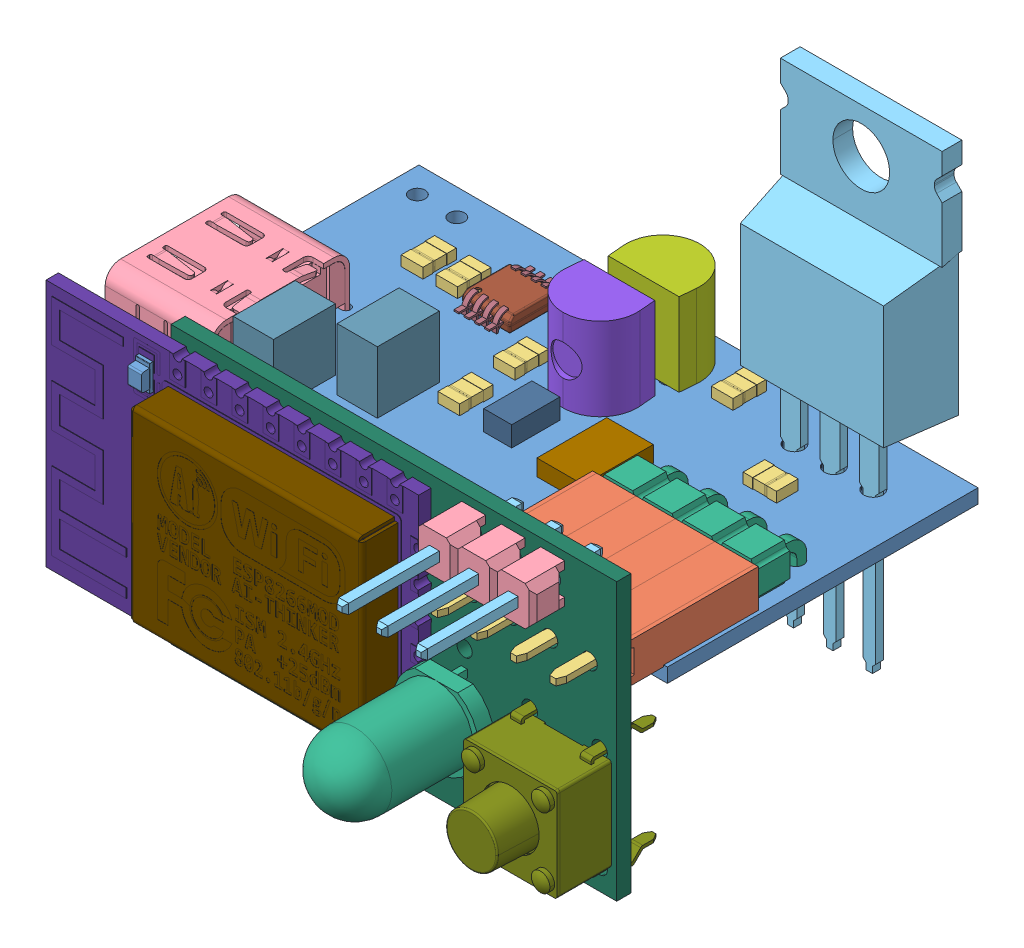
SolidWorks assembly Circuit Assembly, configuration Default. Lengths in mm.
Overall size (37.22 34.92 34.2).
109 component instances, 24 part files, 4 mates.
Components (placement in the parent):
- PowerBoard.step-1: PowerBoard.step [Default] at (-2.5901 17.3095 38.1523) x (1 0 0) z (0 1 0) size (37.14 20 34.92)
  - Board_Power.step-1: Board_Power.step [Default] at origin size (36 20 0.91)
    - Open CASCADE STEP translator 7.5 1.1.1.step-1: Open CASCADE STEP translator 7.5 1.1.1.step [Default] at (0 0 -0.9132) size (36 20 0.91)
  - V1_Power.step-1: V1_Power.step [Default] at origin size (2.8 2.9 1.45)
    - 6479615344.step-1: 6479615344.step [Default] at (29.07 5.49 -0.9132) x (1 0 0) z (0 1 0) size (2.8 1.45 2.9)
  - R9_Power.step-1: R9_Power.step [Default] at origin size (1.45 2.15 0.71)
    - RES_CRGCQ0805F1K2_TEC.step-1: RES_CRGCQ0805F1K2_TEC.step [Default] at (33.56 5.72 -0.9132) x (0 1 0) z (0 0 -1) size (2.15 1.45 0.71)
  - C6_Power.step-1: C6_Power.step [Default] at origin size (2.15 1.45 0.71)
    - RES_CRGCQ0805F1K2_TEC.step-1: RES_CRGCQ0805F1K2_TEC.step [Default] at (28.99 2.19 -0.9132) x (-1 0 0) z (0 0 -1) size (2.15 1.45 0.71)
  - C5_Power.step-1: C5_Power.step [Default] at origin size (2.15 1.45 0.71)
    - RES_CRGCQ0805F1K2_TEC.step-1: RES_CRGCQ0805F1K2_TEC.step [Default] at (32.72 1.75 -0.9132) x (-1 0 0) z (0 0 -1) size (2.15 1.45 0.71)
  - P1_Power.step-1: P1_Power.step [Default] at origin size (6.87 8.94 4.22)
    - USB Connector Type C female 6pin.step-1: USB Connector Type C female 6pin.step [Default] at (-1.142 5.41 1.618) x (0 -1 0) z (-1 0 0) size (8.94 4.22 6.87)
  - Q1_Power.step-1: Q1_Power.step [Default] at origin size (10.41 4.45 29.34)
    - 6479615824.step-1: 6479615824.step [Default] at (30.19 17.34 0) x (1 0 0) z (0 -1 0) size (10.41 29.34 4.45)
      - IRF9540N.step-1: IRF9540N.step [Default] at (-2.54 0 0.8128) size (10.41 29.34 4.45)
  - H2_Power.step-1: H2_Power.step [Default] at origin size (10.16 10.22 4.7)
    - 10129379-904002BLF.step-1: 10129379-904002BLF.step [Default] at (26.56 8.431 1.2177) x (0 -1 0) z (0 0 -1) size (10.22 10.16 4.7)
  - R8_Power.step-1: R8_Power.step [Default] at origin size (2.15 1.45 0.71)
    - RES_CRGCQ0805F1K2_TEC.step-1: RES_CRGCQ0805F1K2_TEC.step [Default] at (29.3 13.35 0) x (-1 0 0) z (0 0 1) size (2.15 1.45 0.71)
  - R7_Power.step-1: R7_Power.step [Default] at origin size (1.45 2.15 0.71)
    - RES_CRGCQ0805F1K2_TEC.step-1: RES_CRGCQ0805F1K2_TEC.step [Default] at (14.4 12.165 0) x (0 1 0) z (0 0 1) size (2.15 1.45 0.71)
  - R6_Power.step-1: R6_Power.step [Default] at origin size (1.45 2.15 0.71)
    - RES_CRGCQ0805F1K2_TEC.step-1: RES_CRGCQ0805F1K2_TEC.step [Default] at (23.1 17.5 0) x (0 1 0) z (0 0 1) size (2.15 1.45 0.71)
  - R5_Power.step-1: R5_Power.step [Default] at origin size (2.15 1.45 0.71)
    - RES_CRGCQ0805F1K2_TEC.step-1: RES_CRGCQ0805F1K2_TEC.step [Default] at (16.6 1.8 0) size (2.15 1.45 0.71)
  - R4_Power.step-1: R4_Power.step [Default] at origin size (2.15 1.45 0.71)
    - RES_CRGCQ0805F1K2_TEC.step-1: RES_CRGCQ0805F1K2_TEC.step [Default] at (8.28 10.59 -0.9132) x (-1 0 0) z (0 0 -1) size (2.15 1.45 0.71)
  - R3_Power.step-1: R3_Power.step [Default] at origin size (1.45 2.15 0.71)
    - RES_CRGCQ0805F1K2_TEC.step-1: RES_CRGCQ0805F1K2_TEC.step [Default] at (5.8 14.835 0) x (0 1 0) z (0 0 1) size (2.15 1.45 0.71)
  - R2_Power.step-1: R2_Power.step [Default] at origin size (1.45 2.15 0.71)
    - RES_CRGCQ0805F1K2_TEC.step-1: RES_CRGCQ0805F1K2_TEC.step [Default] at (8 14.865 0) x (0 1 0) z (0 0 1) size (2.15 1.45 0.71)
  - R1_Power.step-1: R1_Power.step [Default] at origin size (1.45 2.15 0.71)
    - RES_CRGCQ0805F1K2_TEC.step-1: RES_CRGCQ0805F1K2_TEC.step [Default] at (14.6 8.4 0) x (0 1 0) z (0 0 1) size (2.15 1.45 0.71)
  - Q3_Power.step-1: Q3_Power.step [Default] at origin size (4.76 3.63 20.95)
    - 6470186752.step-1: 6470186752.step [Default] at (18.7734 17.507 0) x (1 0 0) z (0 -1 0) size (4.76 20.95 3.63)
      - KSC1008YBU_KSC1008YBU.step-1: KSC1008YBU_KSC1008YBU.step [Default] at (0 0 0.38) size (4.76 20.95 3.63)
  - Q2_Power.step-1: Q2_Power.step [Default] at origin size (4.76 3.63 20.95)
    - 6470186672.step-1: 6470186672.step [Default] at (18.1966 12.903 0) x (-1 0 0) z (0 1 0) size (4.76 20.95 3.63)
      - KSC1008YBU_KSC1008YBU-0.step-1: KSC1008YBU_KSC1008YBU-0.step [Default] at (0 0 0.38) size (4.76 20.95 3.63)
  - M1_Power.step-1: M1_Power.step [Default] at origin size (3 4.5 1.05)
    - 6667053168.step-1: 6667053168.step [Default] at (22.835 8.51 0.15) size (3 4.5 1.05)
      - Extruded.step-1: Extruded.step [Default] at origin size (3 4.5 1.05)
  - IC2_Power.step-1: IC2_Power.step [Default] at origin size (1.8 3.1 1.3)
    - 6667052928.step-1: 6667052928.step [Default] at (18.025 8.6 0.15) size (1.8 3.1 1.3)
      - Extruded-1.step-1: Extruded-1.step [Default] at origin size (1.8 3.1 1.3)
  - IC1_Power.step-1: IC1_Power.step [Default] at origin size (4.33 4.9 1.1)
    - 6470186912.step-1: 6470186912.step [Default] at (11 14.85 0) x (0 1 0) z (0 0 1) size (4.9 4.33 1.1)
      - Body.step-1: Body.step [Default] at (-1.55 -1.55 0) size (3.1 3.1 0.95)
        - Open CASCADE STEP translator 7.5 1.2.1.step-1: Open CASCADE STEP translator 7.5 1.2.1.step [Default] at origin size (3.1 3.1 0.95)
      - Open CASCADE STEP translator 7.5 1.1.step-1: Open CASCADE STEP translator 7.5 1.1.step [Default] at (-1.55 -1.55 0.001) size (0.4 0.4 0.01)
      - Leader.step-1: Leader.step [Default] at (-1.55 -0.975 0) x (-1 0 0) z (0 0 1) size (1.25 0.32 1.05)
      - Leader.step-2: Leader.step [Default] at (-1.55 -0.325 0) x (-1 0 0) z (0 0 1) size (1.25 0.32 1.05)
      - Leader.step-3: Leader.step [Default] at (-1.55 0.325 0) x (-1 0 0) z (0 0 1) size (1.25 0.32 1.05)
      - Leader.step-4: Leader.step [Default] at (-1.55 0.975 0) x (-1 0 0) z (0 0 1) size (1.25 0.32 1.05)
      - Leader.step-5: Leader.step [Default] at (1.55 -0.975 0) size (1.25 0.32 1.05)
      - Leader.step-6: Leader.step [Default] at (1.55 -0.325 0) size (1.25 0.32 1.05)
      - Leader.step-7: Leader.step [Default] at (1.55 0.325 0) size (1.25 0.32 1.05)
      - Leader.step-8: Leader.step [Default] at (1.55 0.975 0) size (1.25 0.32 1.05)
  - C4_Power.step-1: C4_Power.step [Default] at origin size (1.45 2.15 0.71)
    - RES_CRGCQ0805F1K2_TEC.step-1: RES_CRGCQ0805F1K2_TEC.step [Default] at (8.14 7.57 -0.9132) x (0 1 0) z (0 0 -1) size (2.15 1.45 0.71)
  - C3_Power.step-1: C3_Power.step [Default] at origin size (2.59 3.99 8.21)
    - K104K15X7RF5TL2_VIS.step-1: K104K15X7RF5TL2_VIS.step [Default] at (8.05 2.314 0.3048) x (0 1 0) z (0 0 1) size (3.99 2.59 8.21)
  - C2_Power.step-1: C2_Power.step [Default] at origin size (1.45 2.15 0.71)
    - RES_CRGCQ0805F1K2_TEC.step-1: RES_CRGCQ0805F1K2_TEC.step [Default] at (12.08 2.09 -0.9132) x (0 1 0) z (0 0 -1) size (2.15 1.45 0.71)
  - C1_Power.step-1: C1_Power.step [Default] at origin size (2.59 3.99 8.21)
    - K104K15X7RF5TL2_VIS.step-1: K104K15X7RF5TL2_VIS.step [Default] at (11.8 5.254 0.3048) x (0 1 0) z (0 0 1) size (3.99 2.59 8.21)
- SensorPCB.step-1: SensorPCB.step [Default] at (-2.5091 6.1912 41.4964) x (1 0 0) z (0 0 1) size (35.93 17.82 18.09)
  - Board_Sensor.step-1: Board_Sensor.step [Default] at origin size (28.7 17.82 0.91)
    - Open CASCADE STEP translator 7.5 2.1.1.step-1: Open CASCADE STEP translator 7.5 2.1.1.step [Default] at (0 0 -0.9132) size (28.7 17.82 0.91)
  - S2_Sensor.step-1: S2_Sensor.step [Default] at origin size (6 7.9 9.5)
    - 7413577248.step-1: 7413577248.step [Default] at (32.65 4.45 0) x (0 -1 0) z (-1 0 0) size (7.9 9.5 6)
  - S1_Sensor.step-1: S1_Sensor.step [Default] at origin size (3 4.5 1.05)
    - 6479614144.step-1: 6479614144.step [Default] at (12.34 9.02 -2.0132) size (3 4.5 1.05)
      - Extruded.step-1: Extruded.step [Default] at origin size (3 4.5 1.05)
  - IC1_Sensor.step-1: IC1_Sensor.step [Default] at origin size (24 16 3.17)
    - ESP-12F--3DModel-STEP-305423.step-1: ESP-12F--3DModel-STEP-305423.step [Default] at (12.065 8.854 -0.0223) x (1 0 0) z (0 -1 0) size (24 3.17 16)
      - Board.step-1: Board.step [Default] at origin size (24 0.87 16)
      - Shield.step-1: Shield.step [Default] at (3.2 3.17 0) x (1 0 0) z (0 0 -1) size (15.01 2.3 12.11)
      - LED-0603H0.75.step-1: LED-0603H0.75.step [Default] at (-5.5 0.87 -5.3) x (0 0 -1) z (0 1 0) size (1.7 0.9 0.75)
  - H2_Sensor.step-1: H2_Sensor.step [Default] at origin size (10.67 2.54 11.71)
    - PPPC041LFBN-RC.step-1: PPPC041LFBN-RC.step [Default] at (30.35 12.29 -0.926) x (1 0 0) z (0 1 0) size (10.67 11.71 2.54)
      - PPPC021LFBN-RC_C04.step-1: PPPC021LFBN-RC_C04.step [Default] at origin size (10.67 8.51 2.54)
      - Pin - Gold.step-1: Pin - Gold.step [Default] at (-3.81 0 0) size (0.76 3.71 0.41)
      - Pin - Gold.step-2: Pin - Gold.step [Default] at (-1.27 0 0) size (0.76 3.71 0.41)
      - Pin - Gold.step-3: Pin - Gold.step [Default] at (1.27 0 0) size (0.76 3.71 0.41)
      - Pin - Gold.step-4: Pin - Gold.step [Default] at (3.81 0 0) size (0.76 3.71 0.41)
  - R7_Sensor.step-1: R7_Sensor.step [Default] at origin size (1.45 2.15 0.71)
    - RES_CRGCQ0805F1K2_TEC.step-1: RES_CRGCQ0805F1K2_TEC.step [Default] at (17.1 9.6 -0.9132) x (0 1 0) z (0 0 -1) size (2.15 1.45 0.71)
  - R6_Sensor.step-1: R6_Sensor.step [Default] at origin size (2.15 1.45 0.71)
    - RES_CRGCQ0805F1K2_TEC.step-1: RES_CRGCQ0805F1K2_TEC.step [Default] at (22.3 3.8 -0.9132) x (-1 0 0) z (0 0 -1) size (2.15 1.45 0.71)
  - R5_Sensor.step-1: R5_Sensor.step [Default] at origin size (2.15 1.45 0.71)
    - RES_CRGCQ0805F1K2_TEC.step-1: RES_CRGCQ0805F1K2_TEC.step [Default] at (21.3 6.6 -0.9132) x (-1 0 0) z (0 0 -1) size (2.15 1.45 0.71)
  - R4_Sensor.step-1: R4_Sensor.step [Default] at origin size (2.15 1.45 0.71)
    - RES_CRGCQ0805F1K2_TEC.step-1: RES_CRGCQ0805F1K2_TEC.step [Default] at (21.2 9.3 -0.9132) x (-1 0 0) z (0 0 -1) size (2.15 1.45 0.71)
  - R3_Sensor.step-1: R3_Sensor.step [Default] at origin size (2.15 1.45 0.71)
    - RES_CRGCQ0805F1K2_TEC.step-1: RES_CRGCQ0805F1K2_TEC.step [Default] at (13.965 13.1 -0.9132) x (-1 0 0) z (0 0 -1) size (2.15 1.45 0.71)
  - R2_Sensor.step-1: R2_Sensor.step [Default] at origin size (2.15 1.45 0.71)
    - RES_CRGCQ0805F1K2_TEC.step-1: RES_CRGCQ0805F1K2_TEC.step [Default] at (22.235 13 -0.9132) x (-1 0 0) z (0 0 -1) size (2.15 1.45 0.71)
  - R1_Sensor.step-1: R1_Sensor.step [Default] at origin size (2.15 1.45 0.71)
    - RES_CRGCQ0805F1K2_TEC.step-1: RES_CRGCQ0805F1K2_TEC.step [Default] at (11.5 5 -0.9132) x (-1 0 0) z (0 0 -1) size (2.15 1.45 0.71)
  - H1_Sensor.step-1: H1_Sensor.step [Default] at origin size (7.62 2.54 11.68)
    - M20-9990345_asm.step-1: M20-9990345_asm.step [Default] at (34.43 15.83 2.5526) x (-1 0 0) z (0 1 0) size (7.62 11.68 2.54)
      - M20-9990345_asm-1.step-1: M20-9990345_asm-1.step [Default] at origin size (7.62 11.68 2.54)
        - M20-999-MOULD.step-1: M20-999-MOULD.step [Default] at origin size (7.62 2.54 2.54)
        - M20-999-PIN.step-1: M20-999-PIN.step [Default] at (2.54 -5.58 0) x (1 0 0) z (0 0 -1) size (0.64 11.68 0.64)
        - M20-999-PIN.step-2: M20-999-PIN.step [Default] at (5.08 -5.58 0) x (1 0 0) z (0 0 -1) size (0.64 11.68 0.64)
        - M20-999-PIN.step-3: M20-999-PIN.step [Default] at (7.62 -5.58 0) x (1 0 0) z (0 0 -1) size (0.64 11.68 0.64)
- CA GRB LED 5mm-1: CA GRB LED 5mm [Default] at (23.6712 11.8953 42.3091) x (0 1 0) z (1 0 0) size (5.12 34.2 5.5)
Mates (geometry in assembly coordinates):
- Coincident1: coincident anti-aligned: plane of PowerBoard.step-1/H2_Power.step-1/10129379-904002BLF.step-1 through (31.2699 17.1617 32.5769) normal (-1 0 0); plane of SensorPCB.step-1/H2_Sensor.step-1/PPPC041LFBN-RC.step-1/PPPC021LFBN-RC_C04.step-1 through (31.2699 18.8622 33.3313) normal (1 0 0)
- Coincident2: coincident anti-aligned: plane of PowerBoard.step-1/H2_Power.step-1/10129379-904002BLF.step-1 through (31.5899 18.8622 33.1469) normal (0 1 0); plane of SensorPCB.step-1/H2_Sensor.step-1/PPPC041LFBN-RC.step-1/PPPC021LFBN-RC_C04.step-1 through (31.2699 18.8622 33.3313) normal (0 -1 0)
- Coincident3: coincident anti-aligned: plane of PowerBoard.step-1/H2_Power.step-1/10129379-904002BLF.step-1 through (32.2499 17.9672 32.0613) normal (0 0 1); plane of SensorPCB.step-1/H2_Sensor.step-1/PPPC041LFBN-RC.step-1/PPPC021LFBN-RC_C04.step-1 through (32.9209 17.2112 32.0613) normal (0 0 -1)
- Coincident5: coincident anti-aligned: plane of SensorPCB.step-1/IC1_Sensor.step-1/ESP-12F--3DModel-STEP-305423.step-1/Board.step-1 through (9.5559 15.0452 42.3091) normal (0 0 1); plane of CA GRB LED 5mm-1 through (23.6712 11.8953 42.3091) normal (0 0 -1)
